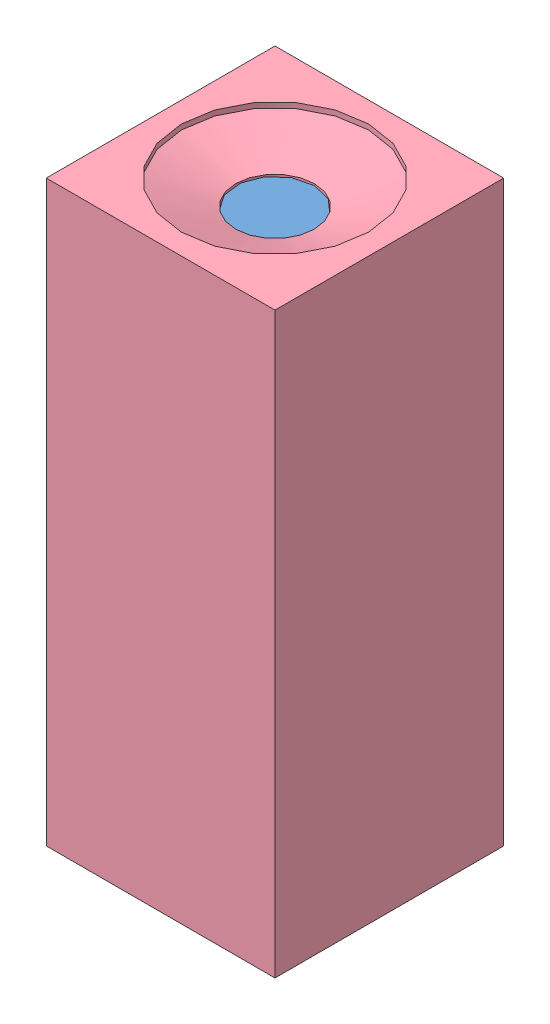
SolidWorks assembly asm_v2, configuration Default. Lengths in mm.
Overall size (154.95 330 154.95).
6 component instances, 4 part files, 12 mates.
Components (placement in the parent):
- 密封盖无握边-1: 密封盖无握边 [Default] at (30.9364 45.781 94.9356) size (110.5 10 110.5)
- flange_seal_v1-1: flange_seal_v1 [Default] at (30.9364 -31.8999 94.9356) x (0 -1 0) z (0.5 0 0.866025) size (28.5 110.5 110.5)
- flange_seal_v1-2: flange_seal_v1 [Default] at (30.9364 -151.538 94.9356) x (0 1 0) z (-0.924225 0 -0.381849) size (28.5 110.5 110.5)
- tube_v1-1: tube_v1 [Default] at (30.9364 -223.719 94.9356) size (110 264 110)
- 密封盖无握边-2: 密封盖无握边 [Default] at (30.9364 -229.219 94.9356) x (-0.792804 0 0.609477) z (0.609477 0 0.792804) size (110.5 10 110.5)
- 主仓模块-1: 主仓模块 [Default] at (30.9364 -259.219 94.9356) x (0 1 0) z (0 0 1) size (330 130.5 130.5)
Mates (geometry in assembly coordinates):
- 同心1: concentric anti-aligned: circle of flange_seal_v1-1; circle of tube_v1-1
- 同心2: concentric aligned: circle of flange_seal_v1-2; circle of tube_v1-1
- 同心4: concentric anti-aligned: circle of flange_seal_v1-2; circle of 密封盖无握边-2
- 距离2: distance = 0 mm anti-aligned: plane of flange_seal_v1-2 through (76.9628 -229.219 113.9517) normal (0 -1 0); plane of 密封盖无握边-2 through (30.9364 -229.219 94.9356) normal (0 1 0)
- 距离3: distance = 0 mm anti-aligned: plane of tube_v1-1 through (30.9364 -223.719 94.9356) normal (0 -1 0); plane of flange_seal_v1-2 through (81.9998 -223.719 116.0328) normal (0 1 0)
- 同心5: concentric anti-aligned: circle of 密封盖无握边-1; circle of flange_seal_v1-1
- 距离4: distance = 0 mm anti-aligned: plane of 密封盖无握边-1 through (30.9364 45.781 94.9356) normal (0 -1 0); plane of flange_seal_v1-1 through (6.0364 45.781 51.8076) normal (0 1 0)
- 距离6: distance = 0 mm anti-aligned: plane of flange_seal_v1-1 through (3.3114 40.281 47.0877) normal (0 -1 0); plane of tube_v1-1 through (30.9364 40.281 94.9356) normal (0 1 0)
- 同心6: concentric aligned: circle of 密封盖无握边-1; circle of flange_seal_v1-1
- 同心7: concentric aligned: circle of flange_seal_v1-2; circle of 密封盖无握边-2
- 同心9: concentric anti-aligned: circle of 密封盖无握边-1; circle of 主仓模块-1
- 重合15: coincident anti-aligned: plane of 密封盖无握边-1 through (30.9364 55.781 94.9356) normal (0 1 0); plane of 主仓模块-1 through (30.9364 55.781 94.9356) normal (0 -1 0)
